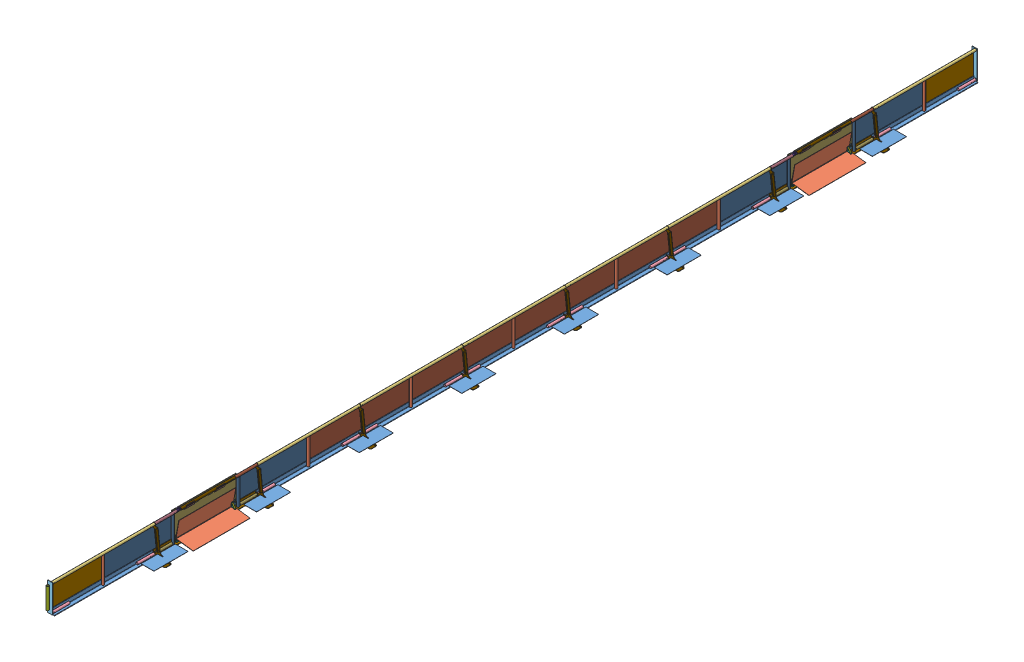
SolidWorks assembly GE-16002-02_ASM, configuration Default. Lengths in mm.
Overall size (399.45 556.51 16611.8).
244 component instances, 37 part files, 0 mates.
Components (placement in the parent):
- FE-00024_ASM-1: FE-00024_ASM [Default] at origin size (109.89 508 1886.05)
  - FE-00005_ASM-1: FE-00005_ASM [Default] at origin size (76.2 507.65 1828.8)
    - FE-00005-01-1: FE-00005-01 [Default] at origin size (76.2 76.2 1828.8)
    - FE-00005-03-1: FE-00005-03 [Default] at (27.432 6.35 914.4) size (42.16 471.23 42.16)
    - FE-00005-04-1: FE-00005-04 [Default] at (27.432 486.5688 0) size (42.16 42.16 1828.8)
    - FE-00005-02-1: FE-00005-02 [Default] at (27.432 27.432 1520.825) size (42.16 42.16 301.62)
    - FE-00005-02-2: FE-00005-02 [Default] at (27.432 27.432 307.975) x (1 0 0) z (0 0 -1) size (42.16 42.16 301.62)
  - FE-00018_ASM-1: FE-00018_ASM [Default] at (-33.6868 6.35 1835.15) size (88.9 501.65 152.5)
    - FE-00018-03-1: FE-00018-03 [Default] at origin size (88.9 501.65 6.35)
    - FE-00018-02-1: FE-00018-02 [Default] at (61.1187 480.2188 -101.6) size (33.4 33.4 101.6)
    - FE-00018-02-2: FE-00018-02 [Default] at (61.1124 21.4312 -101.6) size (33.4 33.4 101.6)
    - FE-00018-01-1: FE-00018-01 [Default] at (23.368 63.5 29.8196) x (1 0 0) z (0 1 0) size (42.16 42.16 374.65)
    - FE-00018-04-1: FE-00018-04 [Default] at (23.368 250.825 6.35) size (19.05 374.65 2.38)
- FE-00029_ASM-1: FE-00029_ASM [Default] at (0 0 -1833.5625) size (76.2 519.84 2006.6)
  - FE-00006_ASM-1: FE-00006_ASM [Default] at origin size (76.2 507.65 1828.8)
    - FE-00006-01-1: FE-00006-01 [Default] at origin size (76.2 76.2 1828.8)
    - FE-00006-10-1: FE-00006-10 [Default] at (27.432 6.35 1496.2188) size (42.16 471.23 42.16)
    - FE-00006-03-1: FE-00006-03 [Default] at (27.432 486.5688 393.7) x (1 0 0) z (0 0 -1) size (42.16 42.16 393.7)
    - FE-00006-02-1: FE-00006-02 [Default] at (27.432 27.432 1520.825) size (42.16 42.16 301.62)
    - FE-00006-02-2: FE-00006-02 [Default] at (27.432 27.432 307.975) x (1 0 0) z (0 0 -1) size (42.16 42.16 301.62)
    - FE-00006-10-2: FE-00006-10 [Default] at (27.432 6.35 332.5876) size (42.16 471.23 42.16)
    - FE-00006-05-1: FE-00006-05 [Default] at (27.432 486.5688 1435.1) size (42.16 42.16 393.7)
    - FE-00006-08-1: FE-00006-08 [Default] at (27.432 486.5688 381) size (48.26 22.22 25.4)
    - FE-00006-09-1: FE-00006-09 [Default] at (12.7 6.35 381) size (25.4 25.4 1066.8)
  - FE-00026-1: FE-00026 [Default] at (27.432 27.432 1651) size (33.4 33.4 355.6)
  - FE-00026-2: FE-00026 [Default] at (27.432 486.5688 1651) size (33.4 33.4 355.6)
  - FE-00027-1: FE-00027 [Default] at (29.0202 469.0397 1500.1875) x (1 0.000041 0) z (0 0.000003 1) size (15.88 50.56 126.92)
  - FE-00027-2: FE-00027 [Default] at (25.8452 469.039 1296.9875) x (-1 -0.000041 0) z (0 -0.000003 -1) size (15.88 50.56 126.92)
  - FE-00028-1: FE-00028 [Default] at (27.432 486.5728 879.1575) x (0 -0.000003 -1) z (1 0.000041 0) size (965.2 42.16 42.16)
  - FE-00031-1: FE-00031 [Default] at (27.432 486.5717 428.3075) x (0 0.000003 1) z (-1 -0.000041 0) size (304.8 33.4 33.4)
- FE-00022_ASM-1: FE-00022_ASM [Default] at (0 0 -3667.125) size (76.2 507.65 2006.6)
  - FE-00005_ASM-1: FE-00005_ASM [Default] at origin size (76.2 507.65 1828.8)
    - FE-00005-01-1: FE-00005-01 [Default] at origin size (76.2 76.2 1828.8)
    - FE-00005-03-1: FE-00005-03 [Default] at (27.432 6.35 914.4) size (42.16 471.23 42.16)
    - FE-00005-04-1: FE-00005-04 [Default] at (27.432 486.5688 0) size (42.16 42.16 1828.8)
    - FE-00005-02-1: FE-00005-02 [Default] at (27.432 27.432 1520.825) size (42.16 42.16 301.62)
    - FE-00005-02-2: FE-00005-02 [Default] at (27.432 27.432 307.975) x (1 0 0) z (0 0 -1) size (42.16 42.16 301.62)
  - FE-00026-1: FE-00026 [Default] at (27.432 27.432 1651) size (33.4 33.4 355.6)
  - FE-00026-2: FE-00026 [Default] at (27.432 486.5688 1651) x (-1 0 0) z (0 0 1) size (33.4 33.4 355.6)
- FE-00022_ASM-2: FE-00022_ASM [Default] at (0 0 -5500.6875) size (76.2 507.65 2006.6)
  - FE-00005_ASM-1: FE-00005_ASM [Default] at origin size (76.2 507.65 1828.8)
    - FE-00005-01-1: FE-00005-01 [Default] at origin size (76.2 76.2 1828.8)
    - FE-00005-03-1: FE-00005-03 [Default] at (27.432 6.35 914.4) size (42.16 471.23 42.16)
    - FE-00005-04-1: FE-00005-04 [Default] at (27.432 486.5688 0) size (42.16 42.16 1828.8)
    - FE-00005-02-1: FE-00005-02 [Default] at (27.432 27.432 1520.825) size (42.16 42.16 301.62)
    - FE-00005-02-2: FE-00005-02 [Default] at (27.432 27.432 307.975) x (1 0 0) z (0 0 -1) size (42.16 42.16 301.62)
  - FE-00026-1: FE-00026 [Default] at (27.432 27.432 1651) size (33.4 33.4 355.6)
  - FE-00026-2: FE-00026 [Default] at (27.432 486.5688 1651) x (-1 0 0) z (0 0 1) size (33.4 33.4 355.6)
- FE-00022_ASM-3: FE-00022_ASM [Default] at (0 0 -7334.25) size (76.2 507.65 2006.6)
  - FE-00005_ASM-1: FE-00005_ASM [Default] at origin size (76.2 507.65 1828.8)
    - FE-00005-01-1: FE-00005-01 [Default] at origin size (76.2 76.2 1828.8)
    - FE-00005-03-1: FE-00005-03 [Default] at (27.432 6.35 914.4) size (42.16 471.23 42.16)
    - FE-00005-04-1: FE-00005-04 [Default] at (27.432 486.5688 0) size (42.16 42.16 1828.8)
    - FE-00005-02-1: FE-00005-02 [Default] at (27.432 27.432 1520.825) size (42.16 42.16 301.62)
    - FE-00005-02-2: FE-00005-02 [Default] at (27.432 27.432 307.975) x (1 0 0) z (0 0 -1) size (42.16 42.16 301.62)
  - FE-00026-1: FE-00026 [Default] at (27.432 27.432 1651) size (33.4 33.4 355.6)
  - FE-00026-2: FE-00026 [Default] at (27.432 486.5688 1651) x (-1 0 0) z (0 0 1) size (33.4 33.4 355.6)
- FE-00022_ASM-4: FE-00022_ASM [Default] at (0 0 -9167.8125) size (76.2 507.65 2006.6)
  - FE-00005_ASM-1: FE-00005_ASM [Default] at origin size (76.2 507.65 1828.8)
    - FE-00005-01-1: FE-00005-01 [Default] at origin size (76.2 76.2 1828.8)
    - FE-00005-03-1: FE-00005-03 [Default] at (27.432 6.35 914.4) size (42.16 471.23 42.16)
    - FE-00005-04-1: FE-00005-04 [Default] at (27.432 486.5688 0) size (42.16 42.16 1828.8)
    - FE-00005-02-1: FE-00005-02 [Default] at (27.432 27.432 1520.825) size (42.16 42.16 301.62)
    - FE-00005-02-2: FE-00005-02 [Default] at (27.432 27.432 307.975) x (1 0 0) z (0 0 -1) size (42.16 42.16 301.62)
  - FE-00026-1: FE-00026 [Default] at (27.432 27.432 1651) size (33.4 33.4 355.6)
  - FE-00026-2: FE-00026 [Default] at (27.432 486.5688 1651) x (-1 0 0) z (0 0 1) size (33.4 33.4 355.6)
- FE-00022_ASM-5: FE-00022_ASM [Default] at (0 0 -11001.375) size (76.2 507.65 2006.6)
  - FE-00005_ASM-1: FE-00005_ASM [Default] at origin size (76.2 507.65 1828.8)
    - FE-00005-01-1: FE-00005-01 [Default] at origin size (76.2 76.2 1828.8)
    - FE-00005-03-1: FE-00005-03 [Default] at (27.432 6.35 914.4) size (42.16 471.23 42.16)
    - FE-00005-04-1: FE-00005-04 [Default] at (27.432 486.5688 0) size (42.16 42.16 1828.8)
    - FE-00005-02-1: FE-00005-02 [Default] at (27.432 27.432 1520.825) size (42.16 42.16 301.62)
    - FE-00005-02-2: FE-00005-02 [Default] at (27.432 27.432 307.975) x (1 0 0) z (0 0 -1) size (42.16 42.16 301.62)
  - FE-00026-1: FE-00026 [Default] at (27.432 27.432 1651) size (33.4 33.4 355.6)
  - FE-00026-2: FE-00026 [Default] at (27.432 486.5688 1651) x (-1 0 0) z (0 0 1) size (33.4 33.4 355.6)
- FE-00029_ASM-2: FE-00029_ASM [Default] at (0 0 -12834.9375) size (76.2 519.84 2006.6)
  - FE-00006_ASM-1: FE-00006_ASM [Default] at origin size (76.2 507.65 1828.8)
    - FE-00006-01-1: FE-00006-01 [Default] at origin size (76.2 76.2 1828.8)
    - FE-00006-10-1: FE-00006-10 [Default] at (27.432 6.35 1496.2188) size (42.16 471.23 42.16)
    - FE-00006-03-1: FE-00006-03 [Default] at (27.432 486.5688 393.7) x (1 0 0) z (0 0 -1) size (42.16 42.16 393.7)
    - FE-00006-02-1: FE-00006-02 [Default] at (27.432 27.432 1520.825) size (42.16 42.16 301.62)
    - FE-00006-02-2: FE-00006-02 [Default] at (27.432 27.432 307.975) x (1 0 0) z (0 0 -1) size (42.16 42.16 301.62)
    - FE-00006-10-2: FE-00006-10 [Default] at (27.432 6.35 332.5876) size (42.16 471.23 42.16)
    - FE-00006-05-1: FE-00006-05 [Default] at (27.432 486.5688 1435.1) size (42.16 42.16 393.7)
    - FE-00006-08-1: FE-00006-08 [Default] at (27.432 486.5688 381) size (48.26 22.22 25.4)
    - FE-00006-09-1: FE-00006-09 [Default] at (12.7 6.35 381) size (25.4 25.4 1066.8)
  - FE-00026-1: FE-00026 [Default] at (27.432 27.432 1651) size (33.4 33.4 355.6)
  - FE-00026-2: FE-00026 [Default] at (27.432 486.5688 1651) size (33.4 33.4 355.6)
  - FE-00027-1: FE-00027 [Default] at (29.0202 469.0397 1500.1875) x (1 0.000041 0) z (0 0.000003 1) size (15.88 50.56 126.92)
  - FE-00027-2: FE-00027 [Default] at (25.8452 469.039 1296.9875) x (-1 -0.000041 0) z (0 -0.000003 -1) size (15.88 50.56 126.92)
  - FE-00028-1: FE-00028 [Default] at (27.432 486.5728 879.1575) x (0 -0.000003 -1) z (1 0.000041 0) size (965.2 42.16 42.16)
  - FE-00031-1: FE-00031 [Default] at (27.432 486.5717 428.3075) x (0 0.000003 1) z (-1 -0.000041 0) size (304.8 33.4 33.4)
- FE-00023_ASM-1: FE-00023_ASM [Default] at (0 0 -14668.5) size (109.88 508 2063.85)
  - FE-00005_ASM-1: FE-00005_ASM [Default] at origin size (76.2 507.65 1828.8)
    - FE-00005-01-1: FE-00005-01 [Default] at origin size (76.2 76.2 1828.8)
    - FE-00005-03-1: FE-00005-03 [Default] at (27.432 6.35 914.4) size (42.16 471.23 42.16)
    - FE-00005-04-1: FE-00005-04 [Default] at (27.432 486.5688 0) size (42.16 42.16 1828.8)
    - FE-00005-02-1: FE-00005-02 [Default] at (27.432 27.432 1520.825) size (42.16 42.16 301.62)
    - FE-00005-02-2: FE-00005-02 [Default] at (27.432 27.432 307.975) x (1 0 0) z (0 0 -1) size (42.16 42.16 301.62)
  - FE-00018_ASM-1: FE-00018_ASM [Default] at (-33.6804 508 -6.35) x (1 0 0) z (0 0 -1) size (88.9 501.65 152.5)
    - FE-00018-03-1: FE-00018-03 [Default] at origin size (88.9 501.65 6.35)
    - FE-00018-02-1: FE-00018-02 [Default] at (61.1187 480.2188 -101.6) size (33.4 33.4 101.6)
    - FE-00018-02-2: FE-00018-02 [Default] at (61.1124 21.4312 -101.6) size (33.4 33.4 101.6)
    - FE-00018-01-1: FE-00018-01 [Default] at (23.368 63.5 29.8196) x (1 0 0) z (0 1 0) size (42.16 42.16 374.65)
    - FE-00018-04-1: FE-00018-04 [Default] at (23.368 250.825 6.35) size (19.05 374.65 2.38)
  - FE-00026-1: FE-00026 [Default] at (27.432 27.432 1651) size (33.4 33.4 355.6)
- FE-00014_ASM-1: FE-00014_ASM [Default] at (28.9388 199.8744 -11920.5375) x (0 0 -1) z (-0.1776 -0.984103 0) size (1016 321.61 335.96)
  - FE-00014-01-1: FE-00014-01 [Default] at origin size (1016 4.76 304.8)
  - FE-00014-02_ASM-1: FE-00014-02_ASM [Default] at (0 -2.286 159.4485) x (1 0 0) z (0 -1 0) size (990.6 43.84 44.07)
    - FE-00014-02-A-1: FE-00014-02-A [Default] at origin size (990.6 43.56 10.92)
    - FE-00014-02-B-1: FE-00014-02-B [Default] at (0 5.4535 -5.7468) x (-1 0 0) z (0 0.99863 -0.052336) size (990.6 43.56 10.92)
    - FE-00014-02-C-1: FE-00014-02-C [Default] at (0 0 -5.461) size (990.6 6.35 6.35)
  - FE-00014-01-2: FE-00014-01 [Default] at (0 162.5711 154.2743) x (1 0 0) z (0 0.99863 -0.052336) size (1016 4.76 304.8)
  - FE-00014-04-1: FE-00014-04 [Default] at (482.6 4.7625 152.4) x (1 0 0) z (0 -1 0) size (25.4 76.2 76.2)
  - FE-00014-05-1: FE-00014-05 [Default] at (495.3 40.2983 116.8642) x (0 0.707107 0.707107) z (0 0.707107 -0.707107) size (82.55 25.4 25.4)
  - FE-00014-03-1: FE-00014-03 [Default] at (0 20.0116 164.0346) x (1 0 0) z (0 -0.052336 -0.99863) size (990.6 19.05 19.05)
- FE-00014_ASM-2: FE-00014_ASM [Default] at (28.9388 199.8744 -919.1625) x (0 0 -1) z (-0.1776 -0.984103 0) size (1016 321.61 335.96)
  - FE-00014-01-1: FE-00014-01 [Default] at origin size (1016 4.76 304.8)
  - FE-00014-02_ASM-1: FE-00014-02_ASM [Default] at (0 -2.286 159.4485) x (1 0 0) z (0 -1 0) size (990.6 43.84 44.07)
    - FE-00014-02-A-1: FE-00014-02-A [Default] at origin size (990.6 43.56 10.92)
    - FE-00014-02-B-1: FE-00014-02-B [Default] at (0 5.4535 -5.7468) x (-1 0 0) z (0 0.99863 -0.052336) size (990.6 43.56 10.92)
    - FE-00014-02-C-1: FE-00014-02-C [Default] at (0 0 -5.461) size (990.6 6.35 6.35)
  - FE-00014-01-2: FE-00014-01 [Default] at (0 162.5711 154.2743) x (1 0 0) z (0 0.99863 -0.052336) size (1016 4.76 304.8)
  - FE-00014-04-1: FE-00014-04 [Default] at (482.6 4.7625 152.4) x (1 0 0) z (0 -1 0) size (25.4 76.2 76.2)
  - FE-00014-05-1: FE-00014-05 [Default] at (495.3 40.2983 116.8642) x (0 0.707107 0.707107) z (0 0.707107 -0.707107) size (82.55 25.4 25.4)
  - FE-00014-03-1: FE-00014-03 [Default] at (0 20.0116 164.0346) x (1 0 0) z (0 -0.052336 -0.99863) size (990.6 19.05 19.05)
- FE-00008-1: FE-00008 [Default] at (-6.35 0 -13754.1) x (0 0 -1) z (1 0 0) size (914.4 482.6 6.35)
- FE-00009-1: FE-00009 [Default] at (-6.35 0 -12509.5) x (0 0 -1) z (1 0 0) size (1244.6 482.6 6.35)
- FE-00009-2: FE-00009 [Default] at (-6.35 0 -10094.1187) x (0 0 -1) z (1 0 0) size (1244.6 482.6 6.35)
- FE-00010-1: FE-00010 [Default] at (-6.35 0 -8265.3188) size (6.35 482.6 1828.8)
- FE-00010-2: FE-00010 [Default] at (-6.35 0 -6436.5188) size (6.35 482.6 1828.8)
- FE-00010-3: FE-00010 [Default] at (-6.35 0 -4607.7188) size (6.35 482.6 1828.8)
- FE-00010-4: FE-00010 [Default] at (-6.35 0 -2778.9187) size (6.35 482.6 1828.8)
- FE-00009-3: FE-00009 [Default] at (-6.35 0 -1534.3187) x (0 0 -1) z (1 0 0) size (1244.6 482.6 6.35)
- FE-00008-2: FE-00008 [Default] at (-6.35 0 1828.8) x (0 0 -1) z (1 0 0) size (914.4 482.6 6.35)
- FE-00009-4: FE-00009 [Default] at (-6.35 0 914.4) x (0 0 -1) z (1 0 0) size (1244.6 482.6 6.35)
- FE-00047_ASM-1: FE-00047_ASM [Default] at (0 254 -919.1625) x (0 -1 0) z (0 0 -1) size (508 53.46 1143)
  - FE-00044-1: FE-00044 [Default] at origin size (508 6.35 1143)
  - FE-00046-1: FE-00046 [Default] at (-161.925 0 254) x (0 -1 0) z (0 0 -1) size (47.11 88.9 152.4)
  - FE-00046-2: FE-00046 [Default] at (-161.925 0 -292.1) x (0 -1 0) z (0 0 -1) size (47.11 88.9 152.4)
  - FE-00045-1: FE-00045 [Default] at (136.525 0 539.75) x (0 -1 0) z (0 0 1) size (12.18 76.2 38.1)
  - FE-00045-2: FE-00045 [Default] at (136.525 0 -539.75) x (0 -1 0) z (0 0 1) size (12.18 76.2 38.1)
  - HW-00047-01-1: HW-00047-01 [Default] at (-180.975 2.4638 304.8) x (-1 0 0) z (0 1 0) size (12.12 12.12 16.29)
  - HW-00047-01-2: HW-00047-01 [Default] at (-180.975 2.4638 203.2) x (-1 0 0) z (0 1 0) size (12.12 12.12 16.29)
  - HW-00047-01-3: HW-00047-01 [Default] at (-180.975 2.4638 -241.3) x (-1 0 0) z (0 1 0) size (12.12 12.12 16.29)
  - HW-00047-01-4: HW-00047-01 [Default] at (-180.975 2.4638 -342.9) x (-1 0 0) z (0 1 0) size (12.12 12.12 16.29)
  - HW-00047-01-5: HW-00047-01 [Default] at (146.05 2.4638 530.225) x (-1 0 0) z (0 1 0) size (12.12 12.12 16.29)
  - HW-00047-01-6: HW-00047-01 [Default] at (165.1 2.4638 549.275) x (-1 0 0) z (0 1 0) size (12.12 12.12 16.29)
  - HW-00047-01-7: HW-00047-01 [Default] at (146.05 2.4638 -549.275) x (-1 0 0) z (0 1 0) size (12.12 12.12 16.29)
  - HW-00047-01-8: HW-00047-01 [Default] at (165.1 2.4638 -530.225) x (-1 0 0) z (0 1 0) size (12.12 12.12 16.29)
  - HW-00047-02_ASM-1: HW-00047-02_ASM [Default] at (-180.975 -2.6568 304.8) x (-1 0 0) z (0 0 1) size (11.11 8.13 12.83)
    - NYLOC_NUT_ASM-1: NYLOC_NUT_ASM [Default] at origin size (11.11 8.13 12.83)
      - NYLOC_NUT_1-1: NYLOC_NUT_1 [Default] at origin size (11.11 8.13 12.83)
      - NYLOC_NUT_2-1: NYLOC_NUT_2 [Default] at origin size (10.65 1.02 10.65)
  - HW-00047-02_ASM-2: HW-00047-02_ASM [Default] at (-180.975 -2.6568 203.2) x (-1 0 0) z (0 0 1) size (11.11 8.13 12.83)
    - NYLOC_NUT_ASM-1: NYLOC_NUT_ASM [Default] at origin size (11.11 8.13 12.83)
      - NYLOC_NUT_1-1: NYLOC_NUT_1 [Default] at origin size (11.11 8.13 12.83)
      - NYLOC_NUT_2-1: NYLOC_NUT_2 [Default] at origin size (10.65 1.02 10.65)
  - HW-00047-02_ASM-3: HW-00047-02_ASM [Default] at (-180.975 -2.6568 -241.3) x (-1 0 0) z (0 0 1) size (11.11 8.13 12.83)
    - NYLOC_NUT_ASM-1: NYLOC_NUT_ASM [Default] at origin size (11.11 8.13 12.83)
      - NYLOC_NUT_1-1: NYLOC_NUT_1 [Default] at origin size (11.11 8.13 12.83)
      - NYLOC_NUT_2-1: NYLOC_NUT_2 [Default] at origin size (10.65 1.02 10.65)
  - HW-00047-02_ASM-4: HW-00047-02_ASM [Default] at (-180.975 -2.6568 -342.9) x (-1 0 0) z (0 0 1) size (11.11 8.13 12.83)
    - NYLOC_NUT_ASM-1: NYLOC_NUT_ASM [Default] at origin size (11.11 8.13 12.83)
      - NYLOC_NUT_1-1: NYLOC_NUT_1 [Default] at origin size (11.11 8.13 12.83)
      - NYLOC_NUT_2-1: NYLOC_NUT_2 [Default] at origin size (10.65 1.02 10.65)
  - HW-00047-02_ASM-5: HW-00047-02_ASM [Default] at (165.1 -2.6568 549.275) x (-1 0 0) z (0 0 1) size (11.11 8.13 12.83)
    - NYLOC_NUT_ASM-1: NYLOC_NUT_ASM [Default] at origin size (11.11 8.13 12.83)
      - NYLOC_NUT_1-1: NYLOC_NUT_1 [Default] at origin size (11.11 8.13 12.83)
      - NYLOC_NUT_2-1: NYLOC_NUT_2 [Default] at origin size (10.65 1.02 10.65)
  - HW-00047-02_ASM-6: HW-00047-02_ASM [Default] at (146.05 -2.6568 530.225) x (-1 0 0) z (0 0 1) size (11.11 8.13 12.83)
    - NYLOC_NUT_ASM-1: NYLOC_NUT_ASM [Default] at origin size (11.11 8.13 12.83)
      - NYLOC_NUT_1-1: NYLOC_NUT_1 [Default] at origin size (11.11 8.13 12.83)
      - NYLOC_NUT_2-1: NYLOC_NUT_2 [Default] at origin size (10.65 1.02 10.65)
  - HW-00047-02_ASM-7: HW-00047-02_ASM [Default] at (165.1 -2.6568 -530.225) x (-1 0 0) z (0 0 1) size (11.11 8.13 12.83)
    - NYLOC_NUT_ASM-1: NYLOC_NUT_ASM [Default] at origin size (11.11 8.13 12.83)
      - NYLOC_NUT_1-1: NYLOC_NUT_1 [Default] at origin size (11.11 8.13 12.83)
      - NYLOC_NUT_2-1: NYLOC_NUT_2 [Default] at origin size (10.65 1.02 10.65)
  - HW-00047-02_ASM-8: HW-00047-02_ASM [Default] at (146.05 -2.6568 -549.275) x (-1 0 0) z (0 0 1) size (11.11 8.13 12.83)
    - NYLOC_NUT_ASM-1: NYLOC_NUT_ASM [Default] at origin size (11.11 8.13 12.83)
      - NYLOC_NUT_1-1: NYLOC_NUT_1 [Default] at origin size (11.11 8.13 12.83)
      - NYLOC_NUT_2-1: NYLOC_NUT_2 [Default] at origin size (10.65 1.02 10.65)
- FE-00047_ASM-2: FE-00047_ASM [Default] at (0 254 -11920.5375) x (0 -1 0) z (0 0 -1) size (508 53.46 1143)
  - FE-00044-1: FE-00044 [Default] at origin size (508 6.35 1143)
  - FE-00046-1: FE-00046 [Default] at (-161.925 0 254) x (0 -1 0) z (0 0 -1) size (47.11 88.9 152.4)
  - FE-00046-2: FE-00046 [Default] at (-161.925 0 -292.1) x (0 -1 0) z (0 0 -1) size (47.11 88.9 152.4)
  - FE-00045-1: FE-00045 [Default] at (136.525 0 539.75) x (0 -1 0) z (0 0 1) size (12.18 76.2 38.1)
  - FE-00045-2: FE-00045 [Default] at (136.525 0 -539.75) x (0 -1 0) z (0 0 1) size (12.18 76.2 38.1)
  - HW-00047-01-1: HW-00047-01 [Default] at (-180.975 2.4638 304.8) x (-1 0 0) z (0 1 0) size (12.12 12.12 16.29)
  - HW-00047-01-2: HW-00047-01 [Default] at (-180.975 2.4638 203.2) x (-1 0 0) z (0 1 0) size (12.12 12.12 16.29)
  - HW-00047-01-3: HW-00047-01 [Default] at (-180.975 2.4638 -241.3) x (-1 0 0) z (0 1 0) size (12.12 12.12 16.29)
  - HW-00047-01-4: HW-00047-01 [Default] at (-180.975 2.4638 -342.9) x (-1 0 0) z (0 1 0) size (12.12 12.12 16.29)
  - HW-00047-01-5: HW-00047-01 [Default] at (146.05 2.4638 530.225) x (-1 0 0) z (0 1 0) size (12.12 12.12 16.29)
  - HW-00047-01-6: HW-00047-01 [Default] at (165.1 2.4638 549.275) x (-1 0 0) z (0 1 0) size (12.12 12.12 16.29)
  - HW-00047-01-7: HW-00047-01 [Default] at (146.05 2.4638 -549.275) x (-1 0 0) z (0 1 0) size (12.12 12.12 16.29)
  - HW-00047-01-8: HW-00047-01 [Default] at (165.1 2.4638 -530.225) x (-1 0 0) z (0 1 0) size (12.12 12.12 16.29)
  - HW-00047-02_ASM-1: HW-00047-02_ASM [Default] at (-180.975 -2.6568 304.8) x (-1 0 0) z (0 0 1) size (11.11 8.13 12.83)
    - NYLOC_NUT_ASM-1: NYLOC_NUT_ASM [Default] at origin size (11.11 8.13 12.83)
      - NYLOC_NUT_1-1: NYLOC_NUT_1 [Default] at origin size (11.11 8.13 12.83)
      - NYLOC_NUT_2-1: NYLOC_NUT_2 [Default] at origin size (10.65 1.02 10.65)
  - HW-00047-02_ASM-2: HW-00047-02_ASM [Default] at (-180.975 -2.6568 203.2) x (-1 0 0) z (0 0 1) size (11.11 8.13 12.83)
    - NYLOC_NUT_ASM-1: NYLOC_NUT_ASM [Default] at origin size (11.11 8.13 12.83)
      - NYLOC_NUT_1-1: NYLOC_NUT_1 [Default] at origin size (11.11 8.13 12.83)
      - NYLOC_NUT_2-1: NYLOC_NUT_2 [Default] at origin size (10.65 1.02 10.65)
  - HW-00047-02_ASM-3: HW-00047-02_ASM [Default] at (-180.975 -2.6568 -241.3) x (-1 0 0) z (0 0 1) size (11.11 8.13 12.83)
    - NYLOC_NUT_ASM-1: NYLOC_NUT_ASM [Default] at origin size (11.11 8.13 12.83)
      - NYLOC_NUT_1-1: NYLOC_NUT_1 [Default] at origin size (11.11 8.13 12.83)
      - NYLOC_NUT_2-1: NYLOC_NUT_2 [Default] at origin size (10.65 1.02 10.65)
  - HW-00047-02_ASM-4: HW-00047-02_ASM [Default] at (-180.975 -2.6568 -342.9) x (-1 0 0) z (0 0 1) size (11.11 8.13 12.83)
    - NYLOC_NUT_ASM-1: NYLOC_NUT_ASM [Default] at origin size (11.11 8.13 12.83)
      - NYLOC_NUT_1-1: NYLOC_NUT_1 [Default] at origin size (11.11 8.13 12.83)
      - NYLOC_NUT_2-1: NYLOC_NUT_2 [Default] at origin size (10.65 1.02 10.65)
  - HW-00047-02_ASM-5: HW-00047-02_ASM [Default] at (165.1 -2.6568 549.275) x (-1 0 0) z (0 0 1) size (11.11 8.13 12.83)
    - NYLOC_NUT_ASM-1: NYLOC_NUT_ASM [Default] at origin size (11.11 8.13 12.83)
      - NYLOC_NUT_1-1: NYLOC_NUT_1 [Default] at origin size (11.11 8.13 12.83)
      - NYLOC_NUT_2-1: NYLOC_NUT_2 [Default] at origin size (10.65 1.02 10.65)
  - HW-00047-02_ASM-6: HW-00047-02_ASM [Default] at (146.05 -2.6568 530.225) x (-1 0 0) z (0 0 1) size (11.11 8.13 12.83)
    - NYLOC_NUT_ASM-1: NYLOC_NUT_ASM [Default] at origin size (11.11 8.13 12.83)
      - NYLOC_NUT_1-1: NYLOC_NUT_1 [Default] at origin size (11.11 8.13 12.83)
      - NYLOC_NUT_2-1: NYLOC_NUT_2 [Default] at origin size (10.65 1.02 10.65)
  - HW-00047-02_ASM-7: HW-00047-02_ASM [Default] at (165.1 -2.6568 -530.225) x (-1 0 0) z (0 0 1) size (11.11 8.13 12.83)
    - NYLOC_NUT_ASM-1: NYLOC_NUT_ASM [Default] at origin size (11.11 8.13 12.83)
      - NYLOC_NUT_1-1: NYLOC_NUT_1 [Default] at origin size (11.11 8.13 12.83)
      - NYLOC_NUT_2-1: NYLOC_NUT_2 [Default] at origin size (10.65 1.02 10.65)
  - HW-00047-02_ASM-8: HW-00047-02_ASM [Default] at (146.05 -2.6568 -549.275) x (-1 0 0) z (0 0 1) size (11.11 8.13 12.83)
    - NYLOC_NUT_ASM-1: NYLOC_NUT_ASM [Default] at origin size (11.11 8.13 12.83)
      - NYLOC_NUT_1-1: NYLOC_NUT_1 [Default] at origin size (11.11 8.13 12.83)
      - NYLOC_NUT_2-1: NYLOC_NUT_2 [Default] at origin size (10.65 1.02 10.65)
- FE-00050-1: FE-00050 [Default] at (6.858 -0.4254 -3.175) size (317.5 508 106.36)
- FE-00050-2: FE-00050 [Default] at (6.858 -0.4254 -1836.7375) size (317.5 508 106.36)
- FE-00050-3: FE-00050 [Default] at (6.858 -0.4254 -3670.3) size (317.5 508 106.36)
- FE-00050-4: FE-00050 [Default] at (6.858 -0.4254 -5503.8625) size (317.5 508 106.36)
- FE-00050-5: FE-00050 [Default] at (6.858 -0.4254 -7337.425) size (317.5 508 106.36)
- FE-00050-6: FE-00050 [Default] at (6.858 -0.4254 -9170.9875) size (317.5 508 106.36)
- FE-00050-7: FE-00050 [Default] at (6.858 -0.4254 -11004.55) size (317.5 508 106.36)
- FE-00050-8: FE-00050 [Default] at (6.858 -0.4254 -12838.1125) size (317.5 508 106.36)
- FE-00015-1: FE-00015 [Default] at (210.058 51.9621 -3.175) x (0 0 -1) z (1 0 0) size (609.6 3.18 228.6)
- FE-00015-2: FE-00015 [Default] at (210.058 51.9621 -1836.7375) x (0 0 -1) z (1 0 0) size (609.6 3.18 228.6)
- FE-00015-3: FE-00015 [Default] at (210.058 51.9621 -3670.3) x (0 0 -1) z (1 0 0) size (609.6 3.18 228.6)
- FE-00015-4: FE-00015 [Default] at (210.058 51.9621 -5503.8625) x (0 0 -1) z (1 0 0) size (609.6 3.18 228.6)
- FE-00015-5: FE-00015 [Default] at (210.058 51.9621 -7337.425) x (0 0 -1) z (1 0 0) size (609.6 3.18 228.6)
- FE-00015-6: FE-00015 [Default] at (210.058 51.9621 -9170.9875) x (0 0 -1) z (1 0 0) size (609.6 3.18 228.6)
- FE-00015-7: FE-00015 [Default] at (210.058 51.9621 -11004.55) x (0 0 -1) z (1 0 0) size (609.6 3.18 228.6)
- FE-00015-8: FE-00015 [Default] at (210.058 51.9621 -12838.1125) x (0 0 -1) z (1 0 0) size (609.6 3.18 228.6)
